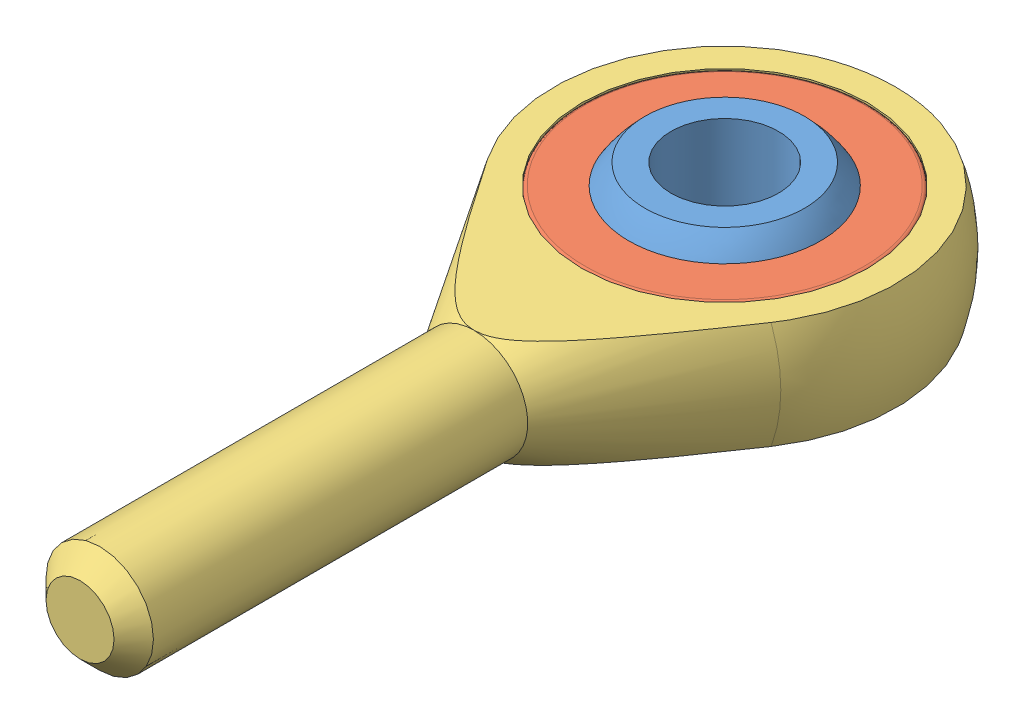
SolidWorks assembly Przegub kulowy_GN 648.2_6, configuration Domyślna. Lengths in mm.
Overall size (20 9 46).
3 component instances, 3 part files, 8 mates.
Components (placement in the parent):
- ROD-END-GN-648.2-1-6-1: ROD-END-GN-648.2-1-6 [6] x (-1 0 0) z (0 0 -1) size (12.66 9 12.66)
- ROD-END-GN-648.2-2-6-1: ROD-END-GN-648.2-2-6 [6] x (0.997964 0 0.063787) z (-0.063787 0 0.997964) size (16 6.75 16)
- ROD-END-GN-648.2-3-6-1: ROD-END-GN-648.2-3-6 [6] at (0 0.375 0) size (20 6 46)
Mates (geometry in assembly coordinates):
- Koncentryczne1: concentric: sphere of ROD-END-GN-648.2-2-6-1; sphere of ROD-END-GN-648.2-1-6-1
- Limit kąta1: limit planar angle = 0 rad aligned: cylinder of ROD-END-GN-648.2-1-6-1 through (0 -11.1 0) axis (0 -1 0) radius 3
- Limit kąta2: limit planar angle = 0 rad aligned: cylinder of ROD-END-GN-648.2-2-6-1 through (0 3.375 0) axis (0 -1 0) radius 8
- Koncentryczne5: concentric anti-aligned: cylinder of ROD-END-GN-648.2-3-6-1 through (0 -2.625 0) axis (0 1 0) radius 8; cylinder of ROD-END-GN-648.2-2-6-1 through (0 3.375 0) axis (0 -1 0) radius 8
- Wspólnie1: coincident aligned: plane of ROD-END-GN-648.2-3-6-1 through (-10 3.375 14) normal (0 1 0); plane of ROD-END-GN-648.2-2-6-1 through (0 3.375 0) normal (0 1 0)
- Wspólnie2: coincident anti-aligned: plane of ROD-END-GN-648.2-1-6-1 through (0 0 0) normal (0 0 -1)
- Wspólnie3: coincident aligned: plane of ROD-END-GN-648.2-1-6-1 through (0 0 0) normal (0 1 0)
- Wspólnie4: coincident anti-aligned: plane of ROD-END-GN-648.2-1-6-1 through (0 0 0) normal (-1 0 0)
